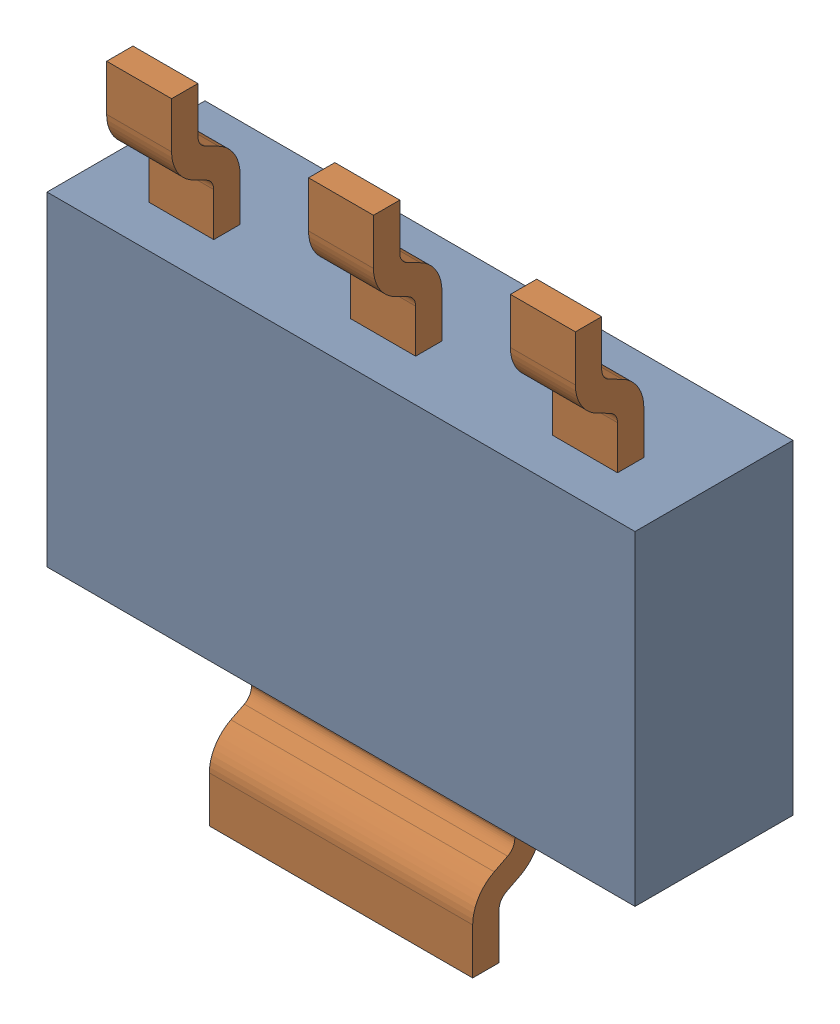
SolidWorks assembly U8, configuration Default. Lengths in mm.
Overall size (6.7 6.96 1.8).
3 component instances, 2 part files, 0 mates.
Components (placement in the parent):
- 1737252000-1: 1737252000 [Default] at (10.1 12 -3.444) size (6.7 3.7 1.8)
  - Extruded-17-1: Extruded-17 [Default] at origin size (6.7 3.7 1.8)
- SOT223-1: SOT223 [Default] at (10.1001 11.9999 -2.424) x (-1 0 0) z (0 -1 0) size (6.5 1.68 6.96)
